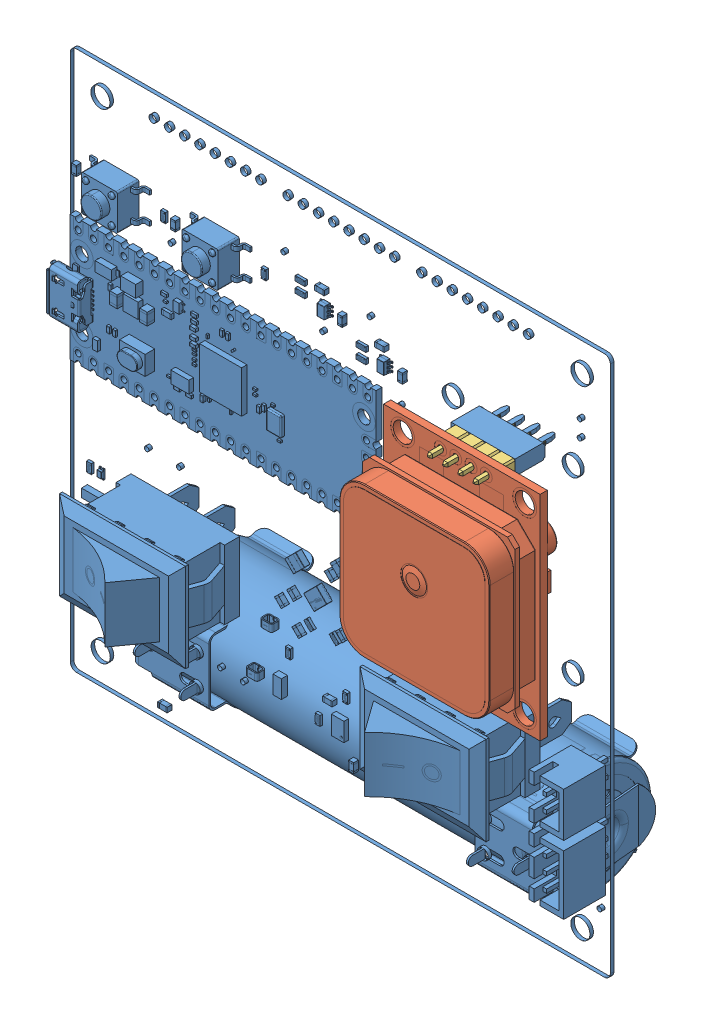
SolidWorks assembly ITEMS PCBA, configuration Default. Lengths in mm.
Overall size (90.14 89.28 37.06).
4 component instances, 3 part files, 2 mates.
Components (placement in the parent):
- ITEMS PCB Rev A-1: ITEMS PCB Rev A [Default] at (-72.5391 -40.3839 12.7465) size (90.14 89.28 37.06)
- A_GPS_main-1: A_GPS_main [Default] at (23.7514 13.1728 20.502) x (0 1 0) z (-1 0 0) size (35.6 12.33 26.08)
- 4-Pin Header - Male - 2.54mm.step-1: 4-Pin Header - Male - 2.54mm.step [Default] at (5.3079 30.6891 20.2865) x (-1 0 0) z (0 0 -1) size (10.16 2.54 11.94)
  - 4-Pin Header - Male - 2.54mm.step-1: 4-Pin Header - Male - 2.54mm.step [Default] x (1 0 0) z (0 -1 0) size (10.16 11.94 2.54)
Mates (geometry in assembly coordinates):
- Parallel2: parallel anti-aligned: plane of A_GPS_main-1 through (-11.8486 -3.1674 17.1725) normal (0 0 -1); plane of 4-Pin Header - Male - 2.54mm.step-1/4-Pin Header - Male - 2.54mm.step-1 through (4.2919 29.4191 20.0325) normal (0 0 1)
- Coincident7: coincident anti-aligned: plane of A_GPS_main-1 through (-11.8486 -3.1674 20.0325) normal (0 0 -1); plane of 4-Pin Header - Male - 2.54mm.step-1/4-Pin Header - Male - 2.54mm.step-1 through (4.2919 29.4191 20.0325) normal (0 0 1)
